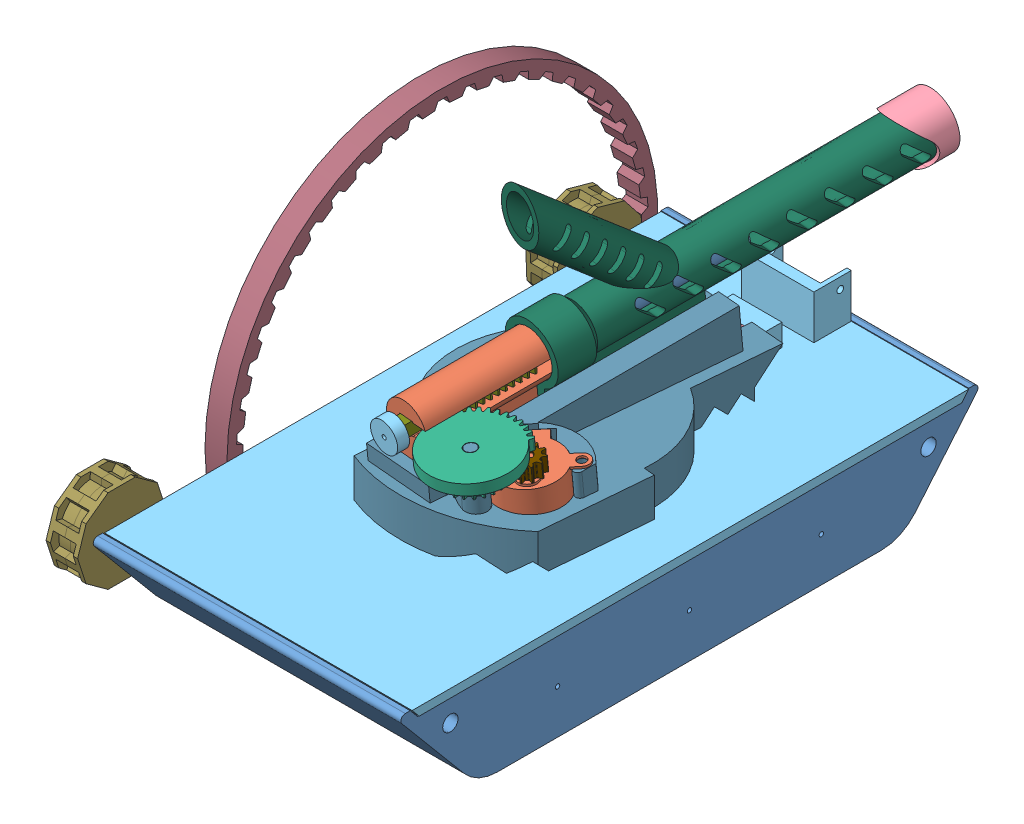
SolidWorks assembly Assemblage, configuration Défaut. Lengths in mm.
Overall size (169.15 236.28 304.54).
49 component instances, 24 part files, 42 mates.
Components (placement in the parent):
- Base Chassis-1: Base Chassis [Default] at origin size (140 44 262.58)
- moteur pas a pas tourelle-1: moteur pas a pas tourelle [Default] at (0.2 35.8302 -0.2611) size (42 28 30.82)
- moteur roue-1: moteur roue [Default] at (-41 30 -108.7766) x (0 0.766044 -0.642788) z (-1 0 0) size (12 10 36)
- photorecepteur-1: photorecepteur [Défaut] at (-10.82 23.8302 -90.7611) x (1 0 0) z (0 -1 0) size (22 9.5 30)
- plaque chassis-1: plaque chassis [Défaut] at (0.2 40 -0.2611) size (140 25.33 253.29)
- batterie-1: batterie [Default] at (0 5 -33.6869) size (100 30 80)
- carte-1: carte [Default] at (0 35 47.1375) x (-1 0 0) z (0 0 1) size (120 30 80)
- assemblage roue-1: assemblage roue [Défaut] at (-75 5 -59.9652) x (0 0.002321 0.999997) z (-1 0 0) size (47 28.34 34)
  - suspension-1: suspension [Default] at origin size (32 20.84 10.07)
  - roue-1: roue [Default] at (-12.5 0 5) size (22 22 9.5)
  - roue-2: roue [Default] at (12.5 0 5) size (22 22 9.5)
  - tige roue-1: tige roue [Default] at (-12.5 0 -5) size (1 1 22)
  - tige roue-2: tige roue [Default] at (0 15 -17) size (1 1 22)
  - tige roue-3: tige roue [Default] at (12.5 0 -5) x (0.994836 0.1015 0) z (0 0 1) size (1 1 22)
- assemblage roue-2: assemblage roue [Défaut] at (-75 5 -0.0352) x (0 -0.002346 0.999997) z (-1 0 0) size (47 28.34 34)
  - suspension-1: suspension [Default] at origin size (32 20.84 10.07)
  - roue-1: roue [Default] at (-12.5 0 5) size (22 22 9.5)
  - roue-2: roue [Default] at (12.5 0 5) size (22 22 9.5)
  - tige roue-1: tige roue [Default] at (-12.5 0 -5) size (1 1 22)
  - tige roue-2: tige roue [Default] at (0 15 -17) size (1 1 22)
  - tige roue-3: tige roue [Default] at (12.5 0 -5) x (0.994836 0.1015 0) z (0 0 1) size (1 1 22)
- assemblage roue-3: assemblage roue [Défaut] at (-75 5.0422 58.875) x (0 -0.075002 0.997183) z (-1 0 0) size (47 28.34 34)
  - suspension-1: suspension [Default] at origin size (32 20.84 10.07)
  - roue-1: roue [Default] at (-12.5 0 5) size (22 22 9.5)
  - roue-2: roue [Default] at (12.5 0 5) size (22 22 9.5)
  - tige roue-1: tige roue [Default] at (-12.5 0 -5) size (1 1 22)
  - tige roue-2: tige roue [Default] at (0 15 -17) size (1 1 22)
  - tige roue-3: tige roue [Default] at (12.5 0 -5) x (0.994836 0.1015 0) z (0 0 1) size (1 1 22)
- axe moteur-1: axe moteur [Default] at (-98.95 30 -108.7766) x (0 0.962478 -0.271361) z (-1 0 0) size (10 10 33.95)
- axe moteur-2: axe moteur [Default] at (-98.95 30.0011 108.7776) x (0 0 -1) z (-1 0 0) size (10 10 33.95)
- engrenage-1: engrenage [Défaut] at (-81.55 30.0011 108.7776) x (0 0 -1) z (-1 0 0) size (40.08 38.12 7.2)
- engrenage-2: engrenage [Défaut] at (-81.55 30 -108.7766) x (0 -0.271361 -0.962478) z (-1 0 0) size (40.08 38.12 7.2)
- engrenage-3: engrenage [Défaut] at (-91.95 30.0011 108.7776) x (0 0 1) z (1 0 0) size (40.08 38.12 7.2)
- engrenage-4: engrenage [Défaut] at (-91.95 30 -108.7766) x (0 0.271361 0.962478) z (1 0 0) size (40.08 38.12 7.2)
- chenille flex-1: chenille flex [Défaut] at (-86.75 32.2788 -39.2947) x (0 0 1) z (-1 0 0) size (196 196 10)
- Assemblage canon-1: Assemblage canon [Défaut] at (0.2 43.8302 -8.2611) x (0.996341 0 0.085469) z (-0.085469 0 0.996341) size (104.22 126.72 243.9)
  - base de tir-1: base de tir [Défaut] at origin size (100 41.6 148.93)
  - canon-1: canon [Default] at (0 44.6162 -8.4689) x (-1 0 0) z (0 0.087156 -0.996195) size (26.4 92.88 168.84)
  - crémaillaire-1: crémaillaire [Carré] at (-0.3536 40.9099 33.8945) x (0 0.996195 0.087156) z (0 0.087156 -0.996195) size (5.66 10.1 139)
  - led-1: led [Défaut] at (0 14.4617 -66.9309) x (0 0 1) z (-1 0 0) size (8.4 5.2 5.2)
  - reducteur-1: reducteur [Défaut] at (36.0518 30.7738 41.7797) x (0.642788 0.066765 -0.763129) z (0 0.996195 0.087156) size (13.93 13.79 6.5)
  - ressort-1: ressort [Default] at (0 50.5812 -76.6485) x (0.389505 -0.91752 -0.080273) z (0 -0.087156 0.996195) size (11.05 11.05 69.24)
  - support crémaillère-1: support crémaillère [Carré] at (0 43.6749 2.29) x (1 0 0) z (0 -0.087156 0.996195) size (20 33.66 70)
  - blocage canon-1: blocage canon [Default] at (-0.2 30.6039 -62.4096) x (-1 0 0) z (0 -0.996195 -0.087156) size (6 3 10)
  - bout canon-1: bout canon [Default] at (0 57.8938 -160.2318) x (-1 0 0) z (0 0.087156 -0.996195) size (24.6 24.6 19.9)
  - bout crémaillère-1: bout crémaillère [Piston] at (-0.3536 50.192 -72.2002) x (-0.447772 0.890745 0.07793) z (0 0.087156 -0.996195) size (13.5 13.5 5)
  - moteur pas a pas tourelle-1: moteur pas a pas tourelle [Default] at (30 9.3001 34.8036) x (-0.642788 -0.066765 0.763129) z (-0.766044 0.056023 -0.640342) size (42 28 30.82)
  - engrenage tir-1: engrenage tir [Défaut] at (26 41.3791 57.0985) x (-0.86708 0.043418 -0.496274) z (0 -0.996195 -0.087156) size (39.75 39.75 12)
  - bout crémaillère-2: bout crémaillère [Piston] at (-0.3536 38.0773 66.2708) x (0.737123 0.673187 0.058896) z (0 -0.087156 0.996195) size (13.5 13.5 5)
Mates (geometry in assembly coordinates):
- Coïncidente1: coincident aligned: plane of batterie-1 through (0 5 -33.6869) normal (1 0 0)
- Coïncidente2: coincident anti-aligned: plane of carte-1 through (0 35 47.1375) normal (-1 0 0)
- Coïncidente3: coincident anti-aligned: plane of Base Chassis-1 through (70 5 -85) normal (0 1 0); plane of carte-1 through (0 5 47.1375) normal (0 -1 0)
- Coïncidente4: coincident anti-aligned: plane of Base Chassis-1 through (70 5 -85) normal (0 1 0); plane of batterie-1 through (0 5 -33.6869) normal (0 -1 0)
- Coïncidente5: coincident anti-aligned: plane of Base Chassis-1 through (0 40 0) normal (0 1 0); plane of plaque chassis-1 through (323.524 40 123.1725) normal (0 -1 0)
- Coïncidente6: coincident anti-aligned: plane of Base Chassis-1 through (65 -0.002 -123.6946) normal (-1 0 0); plane of plaque chassis-1 through (65 38.5 123.1725) normal (1 0 0)
- Coïncidente7: coincident anti-aligned: plane of Base Chassis-1 through (70 44 -127.051) normal (0 0.642788 0.766044); plane of plaque chassis-1 through (323.524 40 -123.6946) normal (0 -0.642788 -0.766044)
- Coaxiale1: concentric aligned: cylinder of moteur pas a pas tourelle-1 through (0.2 54.8302 -0.2611) axis (0 -1 0) radius 14; cylinder of plaque chassis-1 through (0.2 43.8302 -0.2611) axis (0 -1 0) radius 14.25
- Coaxiale2: concentric anti-aligned: cylinder of moteur pas a pas tourelle-1 through (-17.3 53.8302 -0.2611) axis (0 1 0) radius 2; cylinder of plaque chassis-1 through (-17.3 53.8302 -0.2611) axis (0 -1 0) radius 1.9
- Coaxiale3: concentric anti-aligned: cylinder of moteur pas a pas tourelle-1 through (17.7 53.8302 -0.2611) axis (0 1 0) radius 2; cylinder of plaque chassis-1 through (17.7 53.8302 -0.2611) axis (0 -1 0) radius 1.9
- Coïncidente8: coincident anti-aligned: plane of moteur pas a pas tourelle-1 through (-17.3 53.8302 -0.2611) normal (0 -1 0); plane of plaque chassis-1 through (0.2 53.8302 -0.2611) normal (0 1 0)
- Coaxiale6: concentric aligned: cylinder of photorecepteur-1 through (-7.82 50.8302 -95.0037) axis (0 0 1) radius 1.5; cylinder of plaque chassis-1 through (-7.82 50.8302 -126.9086) axis (0 0 1) radius 1.25
- Parallèle3: parallel aligned: plane of plaque chassis-1 through (0.2 53.8302 -0.2611) normal (0 1 0); plane of photorecepteur-1 through (-8.82 53.8302 -89.7611) normal (0 1 0)
- Coïncidente10: coincident anti-aligned: plane of photorecepteur-1 through (-8.82 25.8302 -90.7611) normal (0 0 -1); plane of plaque chassis-1 through (11.32 53.8302 -90.7611) normal (0 0 1)
- Coïncidente11: coincident anti-aligned: plane of Base Chassis-1 through (70 44 -127.051) normal (0 0.642788 0.766044); plane of moteur roue-1 through (-56 24.2454 -110.4749) normal (0 -0.642788 -0.766044)
- Coaxiale9: concentric aligned: cylinder of Base Chassis-1 through (-104.2867 30 -108.7766) axis (1 0 0) radius 6; cylinder of moteur roue-1 through (-56 30 -108.7766) axis (1 0 0) radius 6
- Coïncidente12: coincident anti-aligned: plane of Base Chassis-1 through (-65 -0.002 -123.6946) normal (1 0 0); plane of moteur roue-1 through (-65 30 -108.7766) normal (-1 0 0)
- Coaxiale11: concentric aligned: cylinder of Base Chassis-1 through (-70 20 -60) axis (1 0 0) radius 1; cylinder of assemblage roue-1/tige roue-2 through (-80 20 -60) axis (1 0 0) radius 0.5
- Coaxiale12: concentric aligned: cylinder of Base Chassis-1 through (-70 20 0) axis (1 0 0) radius 1; cylinder of assemblage roue-2/tige roue-2 through (-80 20 0) axis (1 0 0) radius 0.5
- Coaxiale13: concentric aligned: cylinder of Base Chassis-1 through (-70 20 60) axis (1 0 0) radius 1; cylinder of assemblage roue-3/tige roue-2 through (-80 20 60) axis (1 0 0) radius 0.5
- Coïncidente13: coincident anti-aligned: plane of Base Chassis-1 through (-70 25 -85) normal (-1 0 0); plane of assemblage roue-3/suspension-1 through (-70 4.1047 71.3398) normal (1 0 0)
- Coïncidente14: coincident anti-aligned: plane of Base Chassis-1 through (-70 25 -85) normal (-1 0 0); plane of assemblage roue-2/suspension-1 through (-70 4.9707 12.4648) normal (1 0 0)
- Coïncidente15: coincident anti-aligned: plane of Base Chassis-1 through (-70 25 -85) normal (-1 0 0); plane of assemblage roue-1/suspension-1 through (-70 5.0291 -47.4652) normal (1 0 0)
- Coïncidente16: coincident anti-aligned: plane of engrenage-2 through (-86.75 30 -108.7766) normal (-1 0 0); plane of engrenage-4 through (-86.75 30 -108.7766) normal (1 0 0)
- Coïncidente17: coincident anti-aligned: plane of engrenage-1 through (-86.75 30.0011 108.7776) normal (-1 0 0); plane of engrenage-3 through (-86.75 30.0011 108.7776) normal (1 0 0)
- Largeur1: width aligned: plane of engrenage-4 through (-93.95 32.1425 -112.6015) normal (0 -0.962478 0.271361); plane of axe moteur-1 through (-93.95 26.1751 -110.9191) normal (0 0.962478 -0.271361); plane of engrenage-4 through (-73.25 27.9266 -105.0751) normal (0 -0.962478 0.271361); plane of axe moteur-1 through (-73.25 33.7015 -106.7033) normal (0 0.962478 -0.271361)
- Largeur2: width anti-aligned: plane of engrenage-4 through (-93.95 33.8249 -106.6341) normal (0 -0.271361 -0.962478); plane of axe moteur-1 through (-93.95 32.1425 -112.6015) normal (0 0.271361 0.962478); plane of engrenage-4 through (-73.25 33.7015 -106.7033) normal (0 0.271361 0.962478); plane of axe moteur-1 through (-73.25 32.0734 -112.4781) normal (0 -0.271361 -0.962478)
- Largeur3: width anti-aligned: plane of engrenage-2 through (-79.55 32.1425 -112.6015) normal (0 0.271361 0.962478); plane of axe moteur-1 through (-79.55 33.8249 -106.6341) normal (0 -0.271361 -0.962478); plane of engrenage-2 through (-73.25 32.0734 -112.4781) normal (0 -0.271361 -0.962478); plane of axe moteur-1 through (-73.25 33.7015 -106.7033) normal (0 0.271361 0.962478)
- Largeur4: width anti-aligned: plane of engrenage-2 through (-79.55 33.8249 -106.6341) normal (0 -0.962478 0.271361); plane of axe moteur-1 through (-79.55 27.8575 -104.9517) normal (0 0.962478 -0.271361); plane of engrenage-2 through (-73.25 33.7015 -106.7033) normal (0 0.962478 -0.271361); plane of axe moteur-1 through (-73.25 27.9266 -105.0751) normal (0 -0.962478 0.271361)
- Largeur5: width anti-aligned: plane of axe moteur-2 through (-73.25 27.0011 105.7776) normal (0 -1 0); plane of engrenage-1 through (-73.25 33.0011 105.7776) normal (0 1 0); plane of axe moteur-2 through (-79.55 26.9011 111.8776) normal (0 1 0); plane of engrenage-1 through (-79.55 33.1011 111.8776) normal (0 -1 0)
- Largeur6: width anti-aligned: plane of engrenage-1 through (-79.55 33.1011 105.6776) normal (0 0 1); plane of axe moteur-2 through (-79.55 33.1011 111.8776) normal (0 0 -1); plane of engrenage-1 through (-73.25 33.0011 105.7776) normal (0 0 -1); plane of axe moteur-2 through (-73.25 33.0011 111.7776) normal (0 0 1)
- Largeur7: width anti-aligned: plane of engrenage-3 through (-93.95 26.9011 105.6776) normal (0 1 0); plane of axe moteur-2 through (-93.95 33.1011 105.6776) normal (0 -1 0); plane of engrenage-3 through (-73.25 27.0011 105.7776) normal (0 -1 0); plane of axe moteur-2 through (-73.25 33.0011 105.7776) normal (0 1 0)
- Largeur8: width anti-aligned: plane of axe moteur-2 through (-73.25 33.0011 105.7776) normal (0 0 -1); plane of engrenage-3 through (-73.25 33.0011 111.7776) normal (0 0 1); plane of axe moteur-2 through (-93.95 33.1011 105.6776) normal (0 0 1); plane of engrenage-3 through (-93.95 33.1011 111.8776) normal (0 0 -1)
- Coïncidente18: coincident anti-aligned: plane of axe moteur-2 through (-93.95 27.0011 108.7776) normal (1 0 0); plane of engrenage-3 through (-93.95 30.0011 108.7776) normal (-1 0 0)
- Coïncidente19: coincident anti-aligned: plane of axe moteur-1 through (-93.95 29.1859 -111.664) normal (1 0 0); plane of engrenage-4 through (-93.95 30 -108.7766) normal (-1 0 0)
- Coaxiale15: concentric aligned: cylinder of moteur roue-1 through (-75 30 -108.7766) axis (1 0 0) radius 1.5; cylinder of axe moteur-1 through (-75 30 -108.7766) axis (1 0 0) radius 1.7
- Coïncidente22: coincident anti-aligned: plane of moteur roue-1 through (-65 30 -108.7766) normal (-1 0 0); plane of axe moteur-1 through (-65 30 -108.7766) normal (1 0 0)
- Coaxiale16: concentric anti-aligned: cylinder of axe moteur-2 through (-98.95 30.0011 108.7776) axis (-1 0 0) radius 3; cylinder of Base Chassis-1 through (-70 30.0011 108.7776) axis (1 0 0) radius 3.5
- Coïncidente23: coincident aligned: plane of engrenage-1 through (-79.55 30.0011 108.7776) normal (1 0 0); plane of engrenage-2 through (-79.55 30 -108.7766) normal (1 0 0)
- Largeur9: width anti-aligned: plane of chenille flex-1 through (-81.75 120.2788 -39.2947) normal (1 0 0); plane of engrenage-2 through (-91.75 120.2788 -39.2947) normal (-1 0 0); plane of chenille flex-1 through (-81.55 30 -108.7766) normal (-1 0 0); plane of engrenage-4 through (-91.95 30 -108.7766) normal (1 0 0)
- Coaxiale17: concentric aligned: circle of Assemblage canon-1/base de tir-1; cylinder of moteur pas a pas tourelle-1 through (0.2 63.8302 -8.2611) axis (0 -1 0) radius 2.5
- Coïncidente24: coincident: plane of plaque chassis-1 through (323.524 43.8302 126.3864) normal (0 1 0); plane of Assemblage canon-1/base de tir-1 through (0.2 43.8302 -0.2611) normal (0 -1 0)
